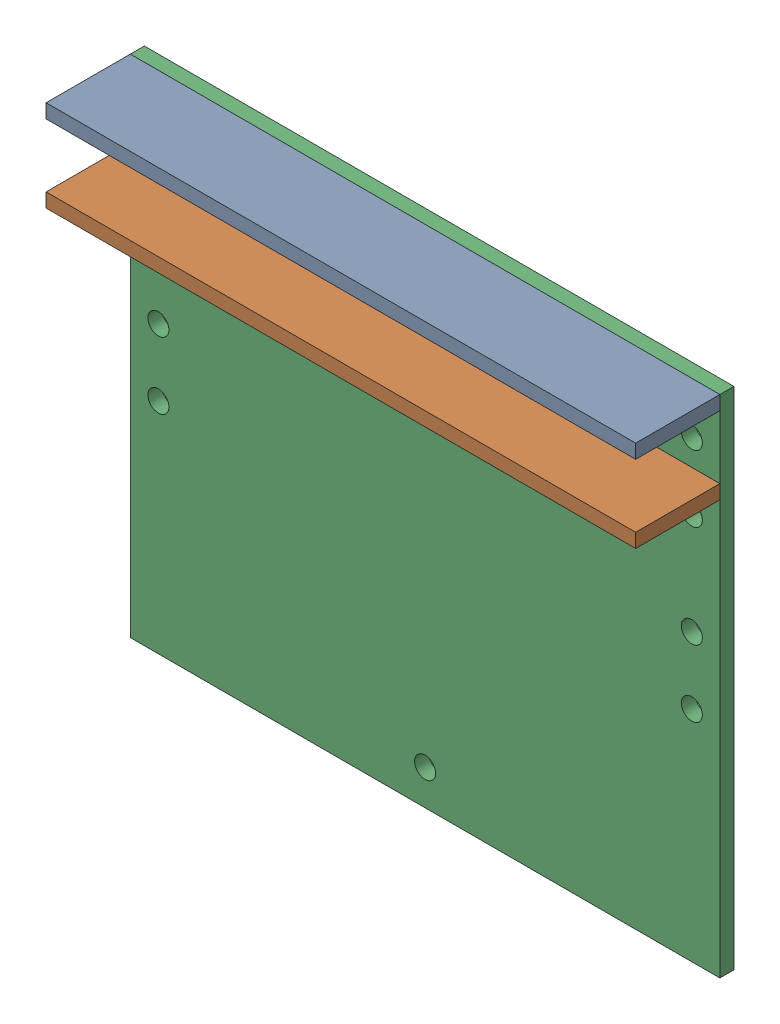
SolidWorks assembly chamber wall ass-1, configuration Default. Lengths in mm.
Overall size (533.4 457.2 88.9).
3 component instances, 2 part files, 0 mates.
Components (placement in the parent):
- Chamber wall flange-1: Chamber wall flange [Default] at (-328.7125 182.3769 97.008) size (533.4 12.7 76.2)
- Chamber wall flange-2: Chamber wall flange [Default] at (-328.7125 112.5269 97.008) size (533.4 12.7 76.2)
- Chamber Walls-1: Chamber Walls [Default] at (-390.878 195.0769 43.2718) size (533.4 457.2 12.7)
